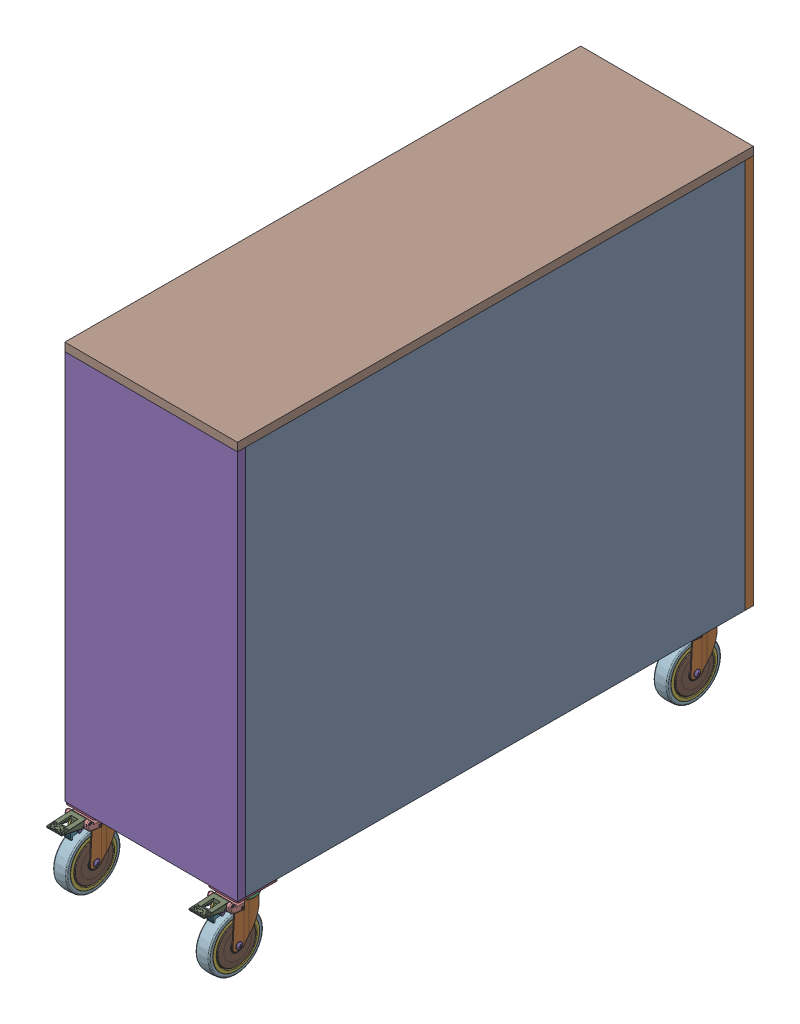
SolidWorks assembly cabinet, configuration Default. Lengths in mm.
Overall size (403.75 1084.15 1249.62).
13 component instances, 6 part files, 36 mates.
Components (placement in the parent):
- backwall-1: backwall [Default] at (2014.0462 655.4278 3064.1611) x (0.003003 0 -0.999995) z (0.999995 0 0.003003) size (1150 900 19.05)
- Side Wall-1: Side Wall [Default] at (1636.6086 655.4278 1893.9724) x (0.999995 0 0.003003) z (-0.003003 0 0.999995) size (400 900 19.05)
- Wheel Joist-1: Wheel Joist [Default] at (2014.0462 655.4278 3064.1611) x (0.003003 0 -0.999995) z (-0.999995 0 -0.003003) size (1150 38.1 88.9)
- Wheel Joist-2: Wheel Joist [Default] at (2017.4997 -244.5722 1914.1663) x (-0.003003 0 0.999995) z (-0.999995 0 -0.003003) size (1150 38.1 88.9)
- 23055T43_Bright-Finish Caster with 3-3-4 x 2-3-4 Plate-1: 23055T43_Bright-Finish Caster with 3-3-4 x 2-3-4 Plate [23055T43] at (1982.3364 -346.1722 1993.436) x (0.999995 0 0.003003) z (-0.003003 0 0.999995) size (69.85 165.1 155.58)
- 23055T43_Bright-Finish Caster with 3-3-4 x 2-3-4 Plate-2: 23055T43_Bright-Finish Caster with 3-3-4 x 2-3-4 Plate [23055T43] at (1671.2951 -346.1722 1973.4519) x (0.999995 0 0.003003) z (-0.003003 0 0.999995) size (69.85 165.1 155.58)
- 23055T43_Bright-Finish Caster with 3-3-4 x 2-3-4 Plate-3: 23055T43_Bright-Finish Caster with 3-3-4 x 2-3-4 Plate [23055T43] at (1668.0132 -346.1722 3066.297) x (0.999995 0 0.003003) z (-0.003003 0 0.999995) size (69.85 165.1 155.58)
- 23055T43_Bright-Finish Caster with 3-3-4 x 2-3-4 Plate-4: 23055T43_Bright-Finish Caster with 3-3-4 x 2-3-4 Plate [23055T43] at (1998.1617 -346.1722 3067.2884) x (0.999995 0 0.003003) z (-0.003003 0 0.999995) size (69.85 165.1 155.58)
- Side Wall-2: Side Wall [Default] at (1633.0407 -244.5722 3082.067) x (0.999995 0 0.003003) z (0.003003 0 -0.999995) size (400 900 19.05)
- Wheel Joist-3: Wheel Joist [Default] at (1725.451 -244.5722 1913.2893) x (-0.003003 0 0.999995) z (-0.999995 0 -0.003003) size (1150 38.1 88.9)
- Wheel Joist-4: Wheel Joist [Default] at (1725.451 617.3278 1913.2893) x (-0.003003 0 0.999995) z (-0.999995 0 -0.003003) size (1150 38.1 88.9)
- Top-1: Top [Default] at (1636.6086 655.4278 1893.9724) x (-0.003003 0 0.999995) z (-0.999995 0 -0.003003) size (1188.1 19.05 400)
- inside shelf-1: inside shelf [Default] at (1633.0979 288.9889 3063.0171) x (0.003003 0 -0.999995) z (0.999995 0 0.003003) size (1150 19.05 380.95)
Mates (geometry in assembly coordinates):
- Coincident28: coincident anti-aligned: plane of backwall-1 through (2014.0462 655.4278 3064.1611) normal (-0.999995 0 -0.003003); plane of Wheel Joist-2 through (2017.4997 -206.4722 1914.1663) normal (0.999995 0 0.003003)
- Distance1: distance = 0 mm aligned: plane of Wheel Joist-2 through (2017.4997 -244.5722 1914.1663) normal (0 -1 0); plane of backwall-1 through (2033.0961 -244.5722 3064.2183) normal (0 -1 0)
- Coincident53: coincident aligned: plane of backwall-1 through (2036.5496 655.4278 1914.2235) normal (0.003003 0 -0.999995); plane of Wheel Joist-2 through (1928.6001 -206.4722 1913.8993) normal (0.003003 0 -0.999995)
- Coincident54: coincident anti-aligned: plane of backwall-1 through (2014.0462 655.4278 3064.1611) normal (-0.999995 0 -0.003003); plane of Wheel Joist-1 through (2014.0462 617.3278 3064.1611) normal (0.999995 0 0.003003)
- Coincident55: coincident aligned: plane of backwall-1 through (2033.0961 655.4278 3064.2183) normal (0 1 0); plane of Wheel Joist-1 through (2014.0462 655.4278 3064.1611) normal (0 1 0)
- Coincident56: coincident aligned: plane of backwall-1 through (2033.0961 655.4278 3064.2183) normal (-0.003003 0 0.999995); plane of Wheel Joist-1 through (1925.1466 617.3278 3063.8941) normal (-0.003003 0 0.999995)
- Coincident59: coincident aligned: plane of backwall-1 through (2033.0961 655.4278 3064.2183) normal (0.999995 0 0.003003); plane of Side Wall-1 through (2036.5496 655.4278 1914.2235) normal (0.999995 0 0.003003)
- Coincident60: coincident aligned: plane of backwall-1 through (2033.0961 -244.5722 3064.2183) normal (0 -1 0); plane of Side Wall-1 through (1636.5514 -244.5722 1913.0223) normal (0 -1 0)
- Coincident64: coincident aligned: plane of backwall-1 through (2033.0961 655.4278 3064.2183) normal (0.999995 0 0.003003); plane of Side Wall-2 through (2033.0961 -244.5722 3064.2183) normal (0.999995 0 0.003003)
- Coincident74: coincident aligned: plane of backwall-1 through (2033.0961 655.4278 3064.2183) normal (0.999995 0 0.003003); plane of 23055T43_Bright-Finish Caster with 3-3-4 x 2-3-4 Plate-4 through (2033.3058 -248.5722 2994.3686) normal (0.999995 0 0.003003)
- Coincident58: coincident anti-aligned: plane of Side Wall-1 through (1636.5514 655.4278 1913.0223) normal (-0.003003 0 0.999995); plane of Wheel Joist-1 through (2017.4997 617.3278 1914.1663) normal (0.003003 0 -0.999995)
- Coincident73: coincident aligned: plane of Side Wall-1 through (1636.6086 655.4278 1893.9724) normal (0.003003 0 -0.999995); plane of Top-1 through (1636.6086 674.4778 1893.9724) normal (0.003003 0 -0.999995)
- Coincident80: coincident aligned: plane of Side Wall-1 through (1636.6086 655.4278 1893.9724) normal (0.003003 0 -0.999995); plane of 23055T43_Bright-Finish Caster with 3-3-4 x 2-3-4 Plate-2 through (1642.9586 -248.5722 1893.9914) normal (0.003003 0 -0.999995)
- Coincident41: coincident aligned: plane of Wheel Joist-1 through (2014.0462 617.3278 3064.1611) normal (0.999995 0 0.003003); plane of 23055T43_Bright-Finish Caster with 3-3-4 x 2-3-4 Plate-1 through (2017.4806 -248.5722 1920.5163) normal (0.999995 0 0.003003)
- Coincident42: coincident: line of Wheel Joist-1 through (1928.6001 617.3278 1913.8993) axis (0 1 0); plane of 23055T43_Bright-Finish Caster with 3-3-4 x 2-3-4 Plate-1 through (1953.9999 -248.5722 1913.9756) normal (0.003003 0 -0.999995)
- Coincident62: coincident anti-aligned: plane of Wheel Joist-1 through (1925.1466 617.3278 3063.8941) normal (-0.003003 0 0.999995); plane of Side Wall-2 through (1633.0979 -244.5722 3063.0171) normal (0.003003 0 -0.999995)
- Coincident63: coincident aligned: plane of Wheel Joist-1 through (2014.0462 655.4278 3064.1611) normal (0 1 0); plane of Side Wall-2 through (1633.0979 655.4278 3063.0171) normal (0 1 0)
- Coincident70: coincident aligned: plane of Wheel Joist-1 through (2014.0462 655.4278 3064.1611) normal (0 1 0); plane of Wheel Joist-4 through (1725.451 655.4278 1913.2893) normal (0 1 0)
- Coincident35: coincident anti-aligned: plane of Wheel Joist-2 through (2017.4997 -244.5722 1914.1663) normal (0 -1 0); plane of 23055T43_Bright-Finish Caster with 3-3-4 x 2-3-4 Plate-1 through (1953.9809 -244.5722 1920.3256) normal (0 1 0)
- Coincident48: coincident anti-aligned: plane of Wheel Joist-2 through (2017.4997 -244.5722 1914.1663) normal (0 -1 0); plane of 23055T43_Bright-Finish Caster with 3-3-4 x 2-3-4 Plate-4 through (1969.8061 -244.5722 2994.1779) normal (0 1 0)
- Coincident79: coincident anti-aligned: plane of 23055T43_Bright-Finish Caster with 3-3-4 x 2-3-4 Plate-2 through (1642.9395 -244.5722 1900.3414) normal (0 1 0); plane of Wheel Joist-3 through (1725.451 -244.5722 1913.2893) normal (0 -1 0)
- Coincident81: coincident aligned: plane of 23055T43_Bright-Finish Caster with 3-3-4 x 2-3-4 Plate-2 through (1636.5895 -248.5722 1900.3223) normal (-0.999995 0 -0.003003); plane of Wheel Joist-3 through (1633.0979 -206.4722 3063.0171) normal (-0.999995 0 -0.003003)
- Coincident76: coincident anti-aligned: plane of 23055T43_Bright-Finish Caster with 3-3-4 x 2-3-4 Plate-3 through (1639.6576 -244.5722 2993.1865) normal (0 1 0); plane of Wheel Joist-3 through (1725.451 -244.5722 1913.2893) normal (0 -1 0)
- Coincident77: coincident aligned: plane of 23055T43_Bright-Finish Caster with 3-3-4 x 2-3-4 Plate-3 through (1639.3906 -248.5722 3082.0861) normal (-0.003003 0 0.999995); plane of Side Wall-2 through (1633.0407 -244.5722 3082.067) normal (-0.003003 0 0.999995)
- Coincident78: coincident aligned: plane of 23055T43_Bright-Finish Caster with 3-3-4 x 2-3-4 Plate-3 through (1633.3076 -248.5722 2993.1674) normal (-0.999995 0 -0.003003); plane of Wheel Joist-3 through (1633.0979 -206.4722 3063.0171) normal (-0.999995 0 -0.003003)
- Coincident75: coincident aligned: plane of 23055T43_Bright-Finish Caster with 3-3-4 x 2-3-4 Plate-4 through (1969.5392 -248.5722 3083.0775) normal (-0.003003 0 0.999995); plane of Side Wall-2 through (1633.0407 -244.5722 3082.067) normal (-0.003003 0 0.999995)
- Coincident65: coincident anti-aligned: plane of Side Wall-2 through (1633.0979 -244.5722 3063.0171) normal (0.003003 0 -0.999995); plane of Wheel Joist-3 through (1721.9975 -206.4722 3063.2841) normal (-0.003003 0 0.999995)
- Coincident66: coincident aligned: plane of Side Wall-2 through (1633.0979 -244.5722 3063.0171) normal (-0.999995 0 -0.003003); plane of Wheel Joist-3 through (1633.0979 -206.4722 3063.0171) normal (-0.999995 0 -0.003003)
- Coincident67: coincident aligned: plane of Side Wall-2 through (1633.0979 -244.5722 3063.0171) normal (0 -1 0); plane of Wheel Joist-3 through (1725.451 -244.5722 1913.2893) normal (0 -1 0)
- Coincident68: coincident aligned: plane of Wheel Joist-3 through (1633.0979 -206.4722 3063.0171) normal (-0.999995 0 -0.003003); plane of Wheel Joist-4 through (1633.0979 655.4278 3063.0171) normal (-0.999995 0 -0.003003)
- Coincident71: coincident aligned: plane of Wheel Joist-4 through (1633.0979 655.4278 3063.0171) normal (-0.999995 0 -0.003003); plane of Top-1 through (1636.6086 674.4778 1893.9724) normal (-0.999995 0 -0.003003)
- Coincident72: coincident anti-aligned: plane of Wheel Joist-4 through (1725.451 655.4278 1913.2893) normal (0 1 0); plane of Top-1 through (1636.6086 655.4278 1893.9724) normal (0 -1 0)
- Coincident82: coincident anti-aligned: plane of backwall-1 through (2014.0462 655.4278 3064.1611) normal (-0.999995 0 -0.003003); plane of inside shelf-1 through (2014.0462 308.0389 3064.1611) normal (0.999995 0 0.003003)
- Coincident83: coincident anti-aligned: plane of Side Wall-2 through (1633.0979 -244.5722 3063.0171) normal (0.003003 0 -0.999995); plane of inside shelf-1 through (1633.0979 308.0389 3063.0171) normal (-0.003003 0 0.999995)
- Coincident85: coincident anti-aligned: plane of backwall-1 through (2036.5496 655.4278 1914.2235) normal (0.003003 0 -0.999995); plane of Side Wall-1 through (1636.5514 655.4278 1913.0223) normal (-0.003003 0 0.999995)
- Coincident86: coincident anti-aligned: plane of Side Wall-1 through (1636.5514 655.4278 1913.0223) normal (-0.003003 0 0.999995); plane of Wheel Joist-4 through (1636.5514 655.4278 1913.0223) normal (0.003003 0 -0.999995)
